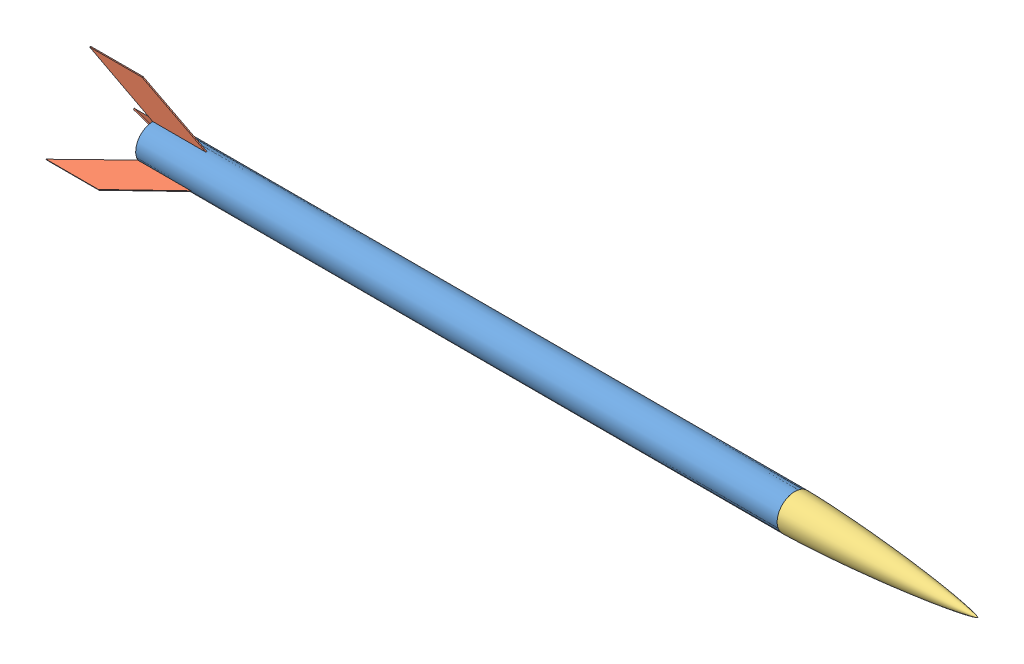
SolidWorks assembly Rocket, configuration Default. Lengths in mm.
Overall size (974.29 67.18 77.58).
5 component instances, 3 part files, 6 mates.
Components (placement in the parent):
- Fuselage-1: Fuselage [Default] at (-147.7757 0 0) x (1 0 0) z (0 -0.555958 0.83121) size (813.19 31 31)
- Fins-1: Fins [Default] at (4309.8355 0 0) size (102.3 29.01 1)
- Fins-2: Fins [Default] at (4309.8355 0 0) x (1 0 0) z (0 -0.866025 -0.5) size (102.3 29.01 1)
- Fins-3: Fins [Default] at (4309.8355 0 0) x (1 0 0) z (0 0.866025 -0.5) size (102.3 29.01 1)
- NoseCone-1: NoseCone [Default] at (161.1032 0 0) x (-1 0 0) z (0 -0.360563 -0.932735) size (161.1 31 31)
Mates (geometry in assembly coordinates):
- Concentric1: concentric anti-aligned: cylinder of Fuselage-1 through (0 0 0) axis (1 0 0) radius 15.5; cylinder of Fins-1 through (-619.4865 0 0) axis (-1 0 0) radius 15.5
- Coincident3: coincident aligned: line of Fuselage-1 through (0 0 0) axis (-1 0 0); line of assembly
- Coincident4: coincident: point of Fuselage-1; point of assembly
- Perpendicular1: perpendicular: plane of Fins-1 through (-619.4865 44.5 0.5) normal (0 1 0); line of assembly
- Distance1: distance = 517.2 mm: line of assembly; moEndPointRef_w of Fins-1
- Coincident5: coincident aligned: circle of Fuselage-1; circle of NoseCone-1
